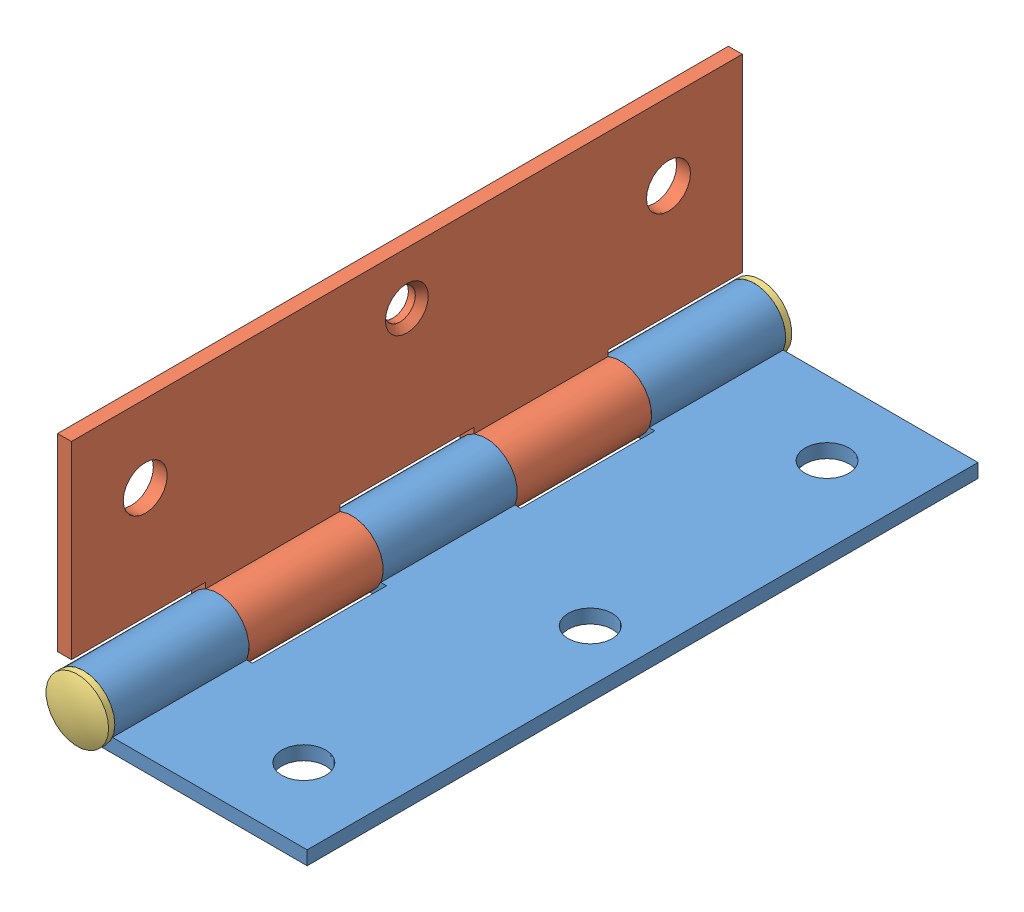
SolidWorks assembly Hinge(McMaster_1598A180), configuration Default. Lengths in mm.
Overall size (28.96 28.96 79.03).
3 component instances, 3 part files, 5 mates.
Components (placement in the parent):
- Hinge(McMaster_1598A180_Part1)-1: Hinge(McMaster_1598A180_Part1) [Default] at origin size (28.96 7.11 76.2)
- Hinge(McMaster_1598A180_Part2)-1: Hinge(McMaster_1598A180_Part2) [Default] x (0 -1 0) z (0 0 1) size (28.96 7.11 76.2)
- Hinge(McMaster_1598A180_Part3)-1: Hinge(McMaster_1598A180_Part3) [Default] at origin size (7.11 7.11 79.03)
Mates (geometry in assembly coordinates):
- Concentric1: concentric aligned: cylinder of Hinge(McMaster_1598A180_Part1)-1 through (0 0 -38.1) axis (0 0 -1) radius 1.9844; cylinder of Hinge(McMaster_1598A180_Part3)-1 through (0 0 39.5173) axis (0 0 -1) radius 1.9844
- Concentric2: concentric aligned: cylinder of Hinge(McMaster_1598A180_Part2)-1 through (0 0 -22.86) axis (0 0 -1) radius 1.9844; cylinder of Hinge(McMaster_1598A180_Part3)-1 through (0 0 39.5173) axis (0 0 -1) radius 1.9844
- Coincident1: coincident anti-aligned: plane of Hinge(McMaster_1598A180_Part1)-1 through (0 0 -22.86) normal (0 0 1); plane of Hinge(McMaster_1598A180_Part2)-1 through (0 0 -22.86) normal (0 0 -1)
- Coincident2: coincident anti-aligned: plane of Hinge(McMaster_1598A180_Part1)-1 through (0 0 -38.1) normal (0 0 -1); plane of Hinge(McMaster_1598A180_Part3)-1 through (3.556 0 -38.1) normal (0 0 1)
- LimitAngle1: limit planar angle = 1.570796 rad aligned: plane of Hinge(McMaster_1598A180_Part1)-1 through (25.4 -1.376 -38.1) normal (0 1 0); plane of Hinge(McMaster_1598A180_Part2)-1 through (-1.376 3.5336 -22.86) normal (1 0 0)
